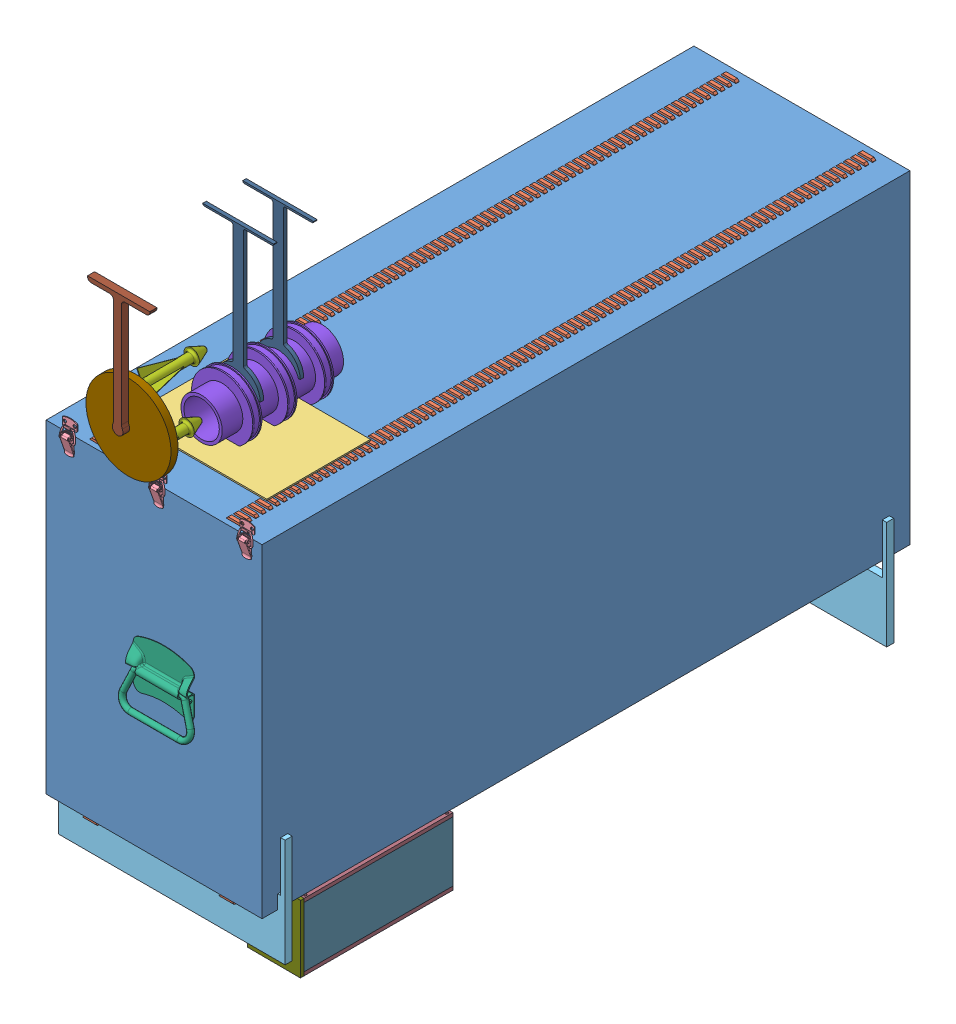
SolidWorks assembly ASSEM_Frame, configuration Default. Lengths in mm.
Overall size (323.44 874.91 963.63).
33 component instances, 16 part files, 0 mates.
Components (placement in the parent):
- PART_MODEL_mainenclosure-1: PART_MODEL_mainenclosure [Default] at (-196.5777 -198.8749 460.3172) size (304.8 457.2 914.4)
- SubASSEM_TopBottomRail-1: SubASSEM_TopBottomRail [Default] at (-35.1843 152.5035 -11.3471) size (214.03 11.24 900)
  - PART_PicRail-1: PART_PicRail [Default] at (-96.4103 108.7891 464.3935) size (21.21 11.24 900)
  - PART_PicRail-2: PART_PicRail [Default] at (96.4103 108.7891 464.3935) size (21.21 11.24 900)
- SubASSEM_TopBottomRail-2: SubASSEM_TopBottomRail [Default] at (-42.6761 -99.8642 20.2946) x (1 0 0) z (0 0 -1) size (214.03 11.24 900)
  - PART_PicRail-1: PART_PicRail [Default] at (-96.4103 108.7891 464.3935) size (21.21 11.24 900)
  - PART_PicRail-2: PART_PicRail [Default] at (96.4103 108.7891 464.3935) size (21.21 11.24 900)
- PART_PeriphMount-1: PART_PeriphMount [Default] at (-136.6949 263.6893 408.682) size (200 2 146.29)
- PART_PeriphMount-2: PART_PeriphMount [Default] at (-137.2986 -210.1103 256.6564) size (200 2 146.29)
- 6082A120_DRAW LATCH-1: 6082A120_DRAW LATCH [Default] at (-163.6999 246.5364 458.9257) x (0.999848 0 -0.017452) z (0 -1 0) size (22 9.09 45.06)
- 6082A120_DRAW LATCH-2: 6082A120_DRAW LATCH [Default] at (-37.4186 247.1167 458.9517) x (1 0 0) z (0 -1 0) size (22 9.09 45.06)
- 6082A120_DRAW LATCH-3: 6082A120_DRAW LATCH [Default] at (89.7729 249.4246 461.8586) x (1 0 0) z (0 -1 0) size (22 9.09 45.06)
- 6082A120_DRAW LATCH-4: 6082A120_DRAW LATCH [Default] at (-195.7921 -190.1166 -431.5669) x (0 0.026177 -0.999657) z (0 0.999657 0.026177) size (22 9.09 45.06)
- stand-1: stand [Default] at (-201.4385 -261.1696 428.1731) size (320 152.4 10)
- stand-2: stand [Default] at (-202.1382 -297.9404 -421.6521) size (320 152.4 10)
- TCH-500-1335802-1: TCH-500-1335802 [Default] at (-31.0424 25.2772 459.4447) size (104.14 96.19 16.48)
- Assembly_torpedo-system1-1: Assembly_torpedo-system1 [Default] at (-41.0648 284.0662 449.6821) x (1 0 0) z (0 0 -1) size (130.63 256.64 287.04)
  - torpedo-1: torpedo [Default] at (-3.8488 -17.569 24.0131) size (29.19 32.22 90.35)
  - barrel-1: barrel [Default] at (-3.8488 -17.569 142.1776) size (86.29 86.29 170)
  - gattling disk-2: gattling disk [Default] at (0.4248 -63.3549 -50.3437) x (0.995672 0.092935 0) z (0 0 1) size (120 120 30)
  - torpedo-2: torpedo [Default] at (4.6984 -109.1408 22.6452) x (0.997465 0.071153 0) z (0 0 1) size (29.19 32.22 90.35)
  - barrel_stand-1: barrel_stand [Default] at (-3.8027 -27.1391 167.6477) size (100 202.74 5)
  - barrel_stand-2: barrel_stand [Default] at (-3.1956 -28.3221 110.6129) size (100 202.74 5)
  - gattling_stand-1: gattling_stand [Default] at (-5.337 -62.5724 -59.8607) size (88 173.98 10)
- ArcScrew_Assembly-1: ArcScrew_Assembly [Default] at (67.2826 -346.3061 238.2365) size (81.1 99.78 223.1)
  - AUVIC ArcScrew 1stDraft-1: AUVIC ArcScrew 1stDraft [Default] at (-53.3633 27.1011 60.9785) x (-0.886365 0.462986 -0.000941) z (-0.000782 0.000536 1) size (60 60 173.02)
  - Top Bottom cap-1: Top Bottom cap [Default] at (-16.0229 -9.004 106.027) x (0.000782 -0.000536 -1) z (0.003451 0.999994 -0.000533) size (210 75 5)
  - Side Plate-1: Side Plate [Default] at (-90.5477 81.1417 -104.0796) x (-0.000782 0.000536 1) z (0.999994 -0.003451 0.000783) size (210 85 5)
  - Side Plate-2: Side Plate [Default] at (-21.0056 -3.9867 106.0205) x (0.000782 -0.000536 -1) z (0.999994 -0.003451 0.000783) size (210 85 5)
  - Top Bottom cap-2: Top Bottom cap [Default] at (-15.7123 80.9955 105.979) x (0.000782 -0.000536 -1) z (0.003451 0.999994 -0.000533) size (210 75 5)
  - BALL-1: BALL [Default] at (-54.8426 56.8222 19.0375) x (-0.712493 0.010853 0.701595) z (-0.348749 -0.873112 -0.34066) size (43 43 43)
  - BALL-2: BALL [Default] at (-54.9732 57.1456 -70.6178) size (43 43 43)
  - Back Plate-1: Back Plate [Default] at (-91.0224 -8.7451 105.9683) x (0.999994 -0.003451 0.000783) z (-0.000782 0.000536 1) size (75 95 5)
